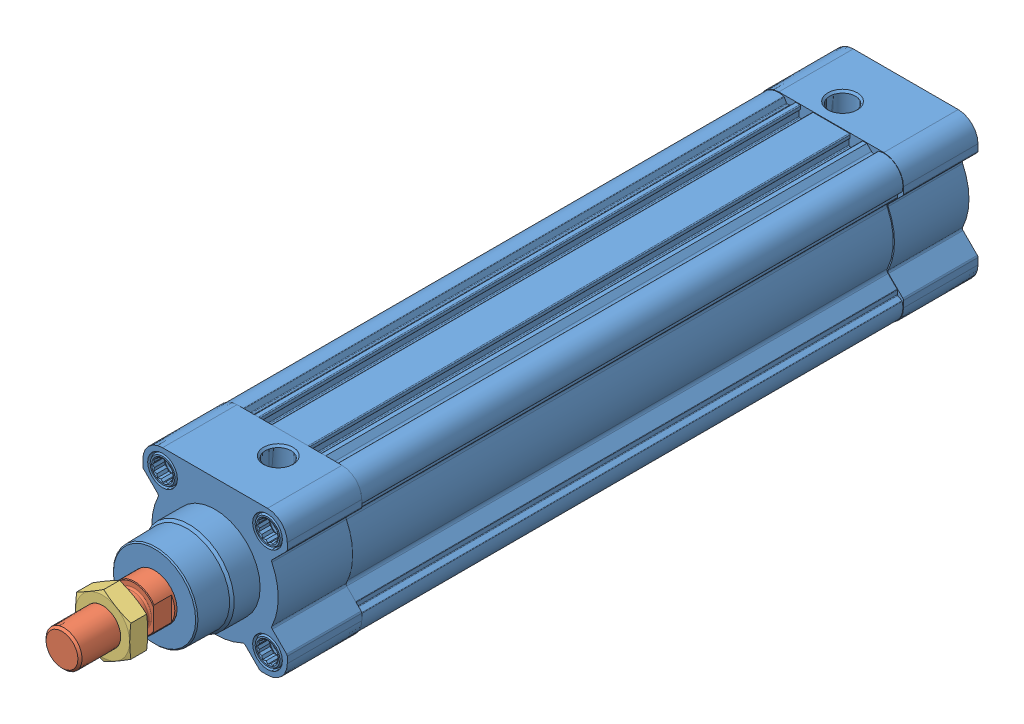
SolidWorks assembly 1376310 DSBC-50-200-PPSA-N3---(0), configuration Default. Lengths in mm.
Overall size (64 64 377.8).
3 component instances, 3 part files, 6 mates.
Components (placement in the parent):
- 1463770 DSBC-50-200-PPSA_(Z_0)-1: 1463770 DSBC-50-200-PPSA_(Z_0) [Default] at origin size (64 64 336.8)
- 1463770 DSBC-50-200_(K)-1: 1463770 DSBC-50-200_(K) [Default] at origin size (50 50 340.8)
- DIN-439-B - M16x1_5(F)-1: DIN-439-B - M16x1_5(F) [Default] at (0 0 49.8) x (1 0 0) z (0 -1 0) size (24 8 27.71)
Mates (geometry in assembly coordinates):
- LimitDistance1: limit distance = 0 mm anti-aligned: plane of 1463770 DSBC-50-200-PPSA_(Z_0)-1 through (0 0 -273) normal (0 0 1); plane of 1463770 DSBC-50-200_(K)-1 through (0 0 -273) normal (0 0 -1)
- Coincident1: coincident anti-aligned: line of 1463770 DSBC-50-200-PPSA_(Z_0)-1 through (0 0 80.9) axis (0 0 -1); line of 1463770 DSBC-50-200_(K)-1 through (0 0 -50) axis (0 0 1)
- Angle2: planar angle = 1.570796 rad anti-aligned: plane of 1463770 DSBC-50-200_(K)-1 through (0 0 0) normal (0 1 0); plane of 1463770 DSBC-50-200-PPSA_(Z_0)-1 through (0 0 0) normal (1 0 0)
- Distance1: distance = 0 mm anti-aligned: plane of 1463770 DSBC-50-200_(K)-1 through (0 0 49.8) normal (0 0 -1); plane of DIN-439-B - M16x1_5(F)-1 through (0 0 49.8) normal (0 0 1)
- Coincident2: coincident anti-aligned: line of 1463770 DSBC-50-200_(K)-1 through (0 0 -80.9) axis (0 0 1); line of DIN-439-B - M16x1_5(F)-1 through (0 0 99.8) axis (0 0 -1)
- Angle5: planar angle = 0 rad aligned: plane of DIN-439-B - M16x1_5(F)-1 through (0 0 49.8) normal (1 0 0); plane of 1463770 DSBC-50-200_(K)-1 through (0 0 0) normal (1 0 0)
